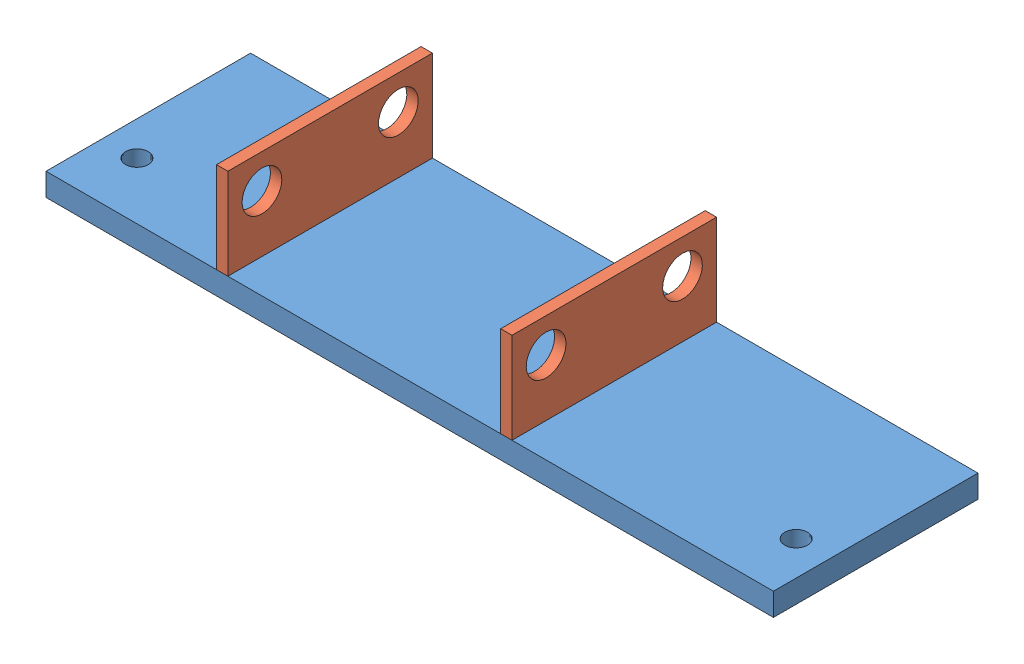
SolidWorks assembly Cam_Support_Ass_3, configuration Default. Lengths in mm.
Overall size (447.04 64.13 152.4).
3 component instances, 2 part files, 3 mates.
Components (placement in the parent):
- 01-020-00-0-1: 01-020-00-0 [Default] at (-198.1826 -10.9875 112.043) size (447.04 13.97 152.4)
- Cam Support Tab-1: Cam Support Tab [Default] at (-102.9326 1.7125 112.043) x (0 1 0) z (-1 0 0) size (50.8 114.3 6.35)
- Cam Support Tab-2: Cam Support Tab [Default] at (55.8174 1.7125 112.043) x (0 1 0) z (-1 0 0) size (50.8 114.3 6.35)
Mates (geometry in assembly coordinates):
- Coincident1: coincident anti-aligned: plane of 01-020-00-0-1 through (-198.1826 1.7125 -2.257) normal (0 1 0); plane of Cam Support Tab-1 through (-102.9326 1.7125 -2.257) normal (0 -1 0)
- Coincident2: coincident aligned: line of 01-020-00-0-1 through (208.2174 1.7125 -2.257) axis (-1 0 0); line of Cam Support Tab-1 through (-96.5826 1.7125 -2.257) axis (-1 0 0)
- Distance1: distance = 95.25 mm: line of Cam Support Tab-1 through (-102.9326 1.7125 -2.257) axis (0 0 1); line of 01-020-00-0-1 through (-198.1826 1.7125 -2.257) axis (0 0 1)
